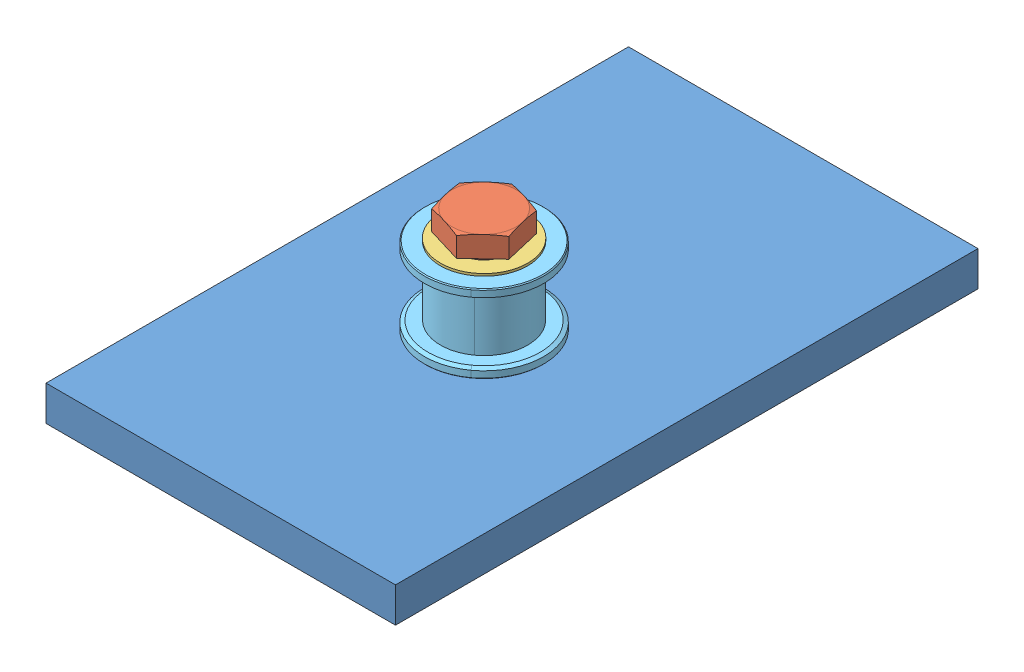
SolidWorks assembly Pulley Support, configuration Default. Lengths in mm.
Overall size (38.1 22.54 63.5).
9 component instances, 5 part files, 13 mates.
Components (placement in the parent):
- Wood support 4-1: Wood support 4 [Default] at (1.8326 25.4952 65.4745) size (38.1 3.81 63.5)
- Hexagonal Bolt M4-25-1: Hexagonal Bolt M4-25 [Default] at (21.0153 38.3132 36.8995) x (0 -1 0) z (-0.728918 0 0.684602) size (22.54 7 8.08)
  - Hexagonal Bolt M4-25-1: Hexagonal Bolt M4-25 [Default] at origin size (28.05 7 8.08)
- Washer-1: Washer [Default] at (21.0153 38.3132 36.8995) x (-0.092668 0 -0.995697) z (-0.995697 0 0.092668) size (9.53 0.25 9.53)
- Washer-2: Washer [Default] at (21.0153 25.2412 36.8995) x (-0.891041 0 -0.453923) z (0.453923 0 -0.891041) size (9.53 0.25 9.53)
- Hexagonal Nut M4-1: Hexagonal Nut M4 [Default] at (21.0153 25.2412 36.8995) x (-0.955003 0 0.296596) z (0.296596 0 0.955003) size (7 3.45 8.08)
  - Hexagonal Nut M4-1: Hexagonal Nut M4 [Default] x (0 -1 0) z (-1 0 0) size (3.45 8.08 7)
- GT2_Pulley_No_Teeth.step-1: GT2_Pulley_No_Teeth.step [Default] at (21.373 20.8092 34.8369) x (-0.588948 0 -0.808171) z (0 1 0) size (13 13 8.5)
- Washer-3: Washer [Default] at (21.0153 29.3052 36.8995) x (-0.288637 0 0.957438) z (-0.957438 0 -0.288637) size (9.53 0.25 9.53)
Mates (geometry in assembly coordinates):
- Parallel4: parallel anti-aligned: plane of Hexagonal Bolt M4-25-1/Hexagonal Bolt M4-25-1 through (23.0348 38.3132 39.0499) normal (0 -1 0); plane of Washer-1 through (21.0153 38.3132 36.8995) normal (0 1 0)
- Concentric5: concentric aligned: circle of Hexagonal Bolt M4-25-1/Hexagonal Bolt M4-25-1; circle of Washer-1
- Coincident26: coincident anti-aligned: plane of Hexagonal Bolt M4-25-1/Hexagonal Bolt M4-25-1 through (23.0348 38.3132 39.0499) normal (0 -1 0); plane of Washer-1 through (21.0153 38.3132 36.8995) normal (0 1 0)
- Concentric11: concentric anti-aligned: circle of Washer-1; circle of Washer-3
- Coincident28: coincident anti-aligned: plane of Wood support 4-1 through (1.8326 29.3052 65.4745) normal (0 1 0); plane of Washer-3 through (21.0153 29.3052 36.8995) normal (0 -1 0)
- Concentric12: concentric aligned: circle of Wood support 4-1; circle of Washer-1
- Concentric13: concentric anti-aligned: circle of Washer-1; circle of Washer-2
- Coincident30: coincident anti-aligned: plane of Washer-2 through (21.0153 25.2412 36.8995) normal (0 -1 0); plane of Hexagonal Nut M4-1/Hexagonal Nut M4-1 through (22.3366 25.2412 41.1541) normal (0 1 0)
- Concentric14: concentric aligned: circle of Washer-1; circle of Hexagonal Nut M4-1/Hexagonal Nut M4-1
- Coincident33: coincident anti-aligned: plane of Wood support 4-1 through (1.8326 25.4952 65.4745) normal (0 -1 0); plane of Washer-2 through (21.0153 25.4952 36.8995) normal (0 1 0)
- Concentric16: concentric aligned: circle of GT2_Pulley_No_Teeth.step-1; circle of Washer-3
- Coincident35: coincident anti-aligned: plane of GT2_Pulley_No_Teeth.step-1 through (21.0153 29.5592 36.8995) normal (0 -1 0); plane of Washer-3 through (21.0153 29.5592 36.8995) normal (0 1 0)
- Coincident36: coincident anti-aligned: plane of Washer-1 through (21.0153 38.0592 36.8995) normal (0 -1 0); plane of GT2_Pulley_No_Teeth.step-1 through (21.0153 38.0592 36.8995) normal (0 1 0)
